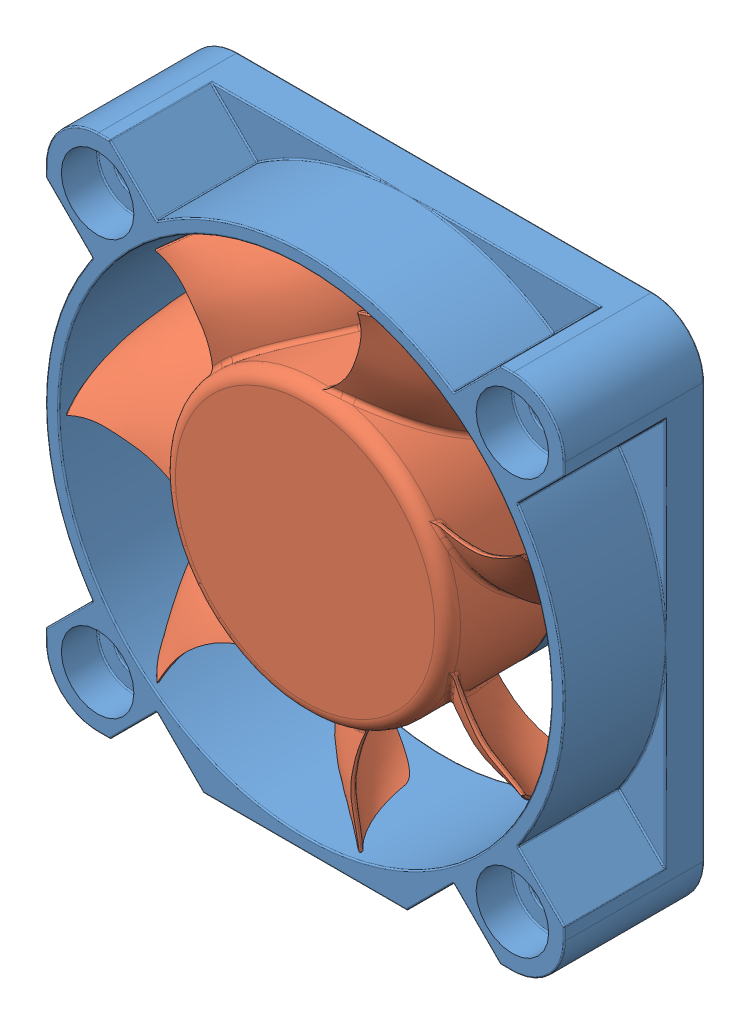
SolidWorks assembly 40mm-fan, configuration По умолчанию. Lengths in mm.
Overall size (40.01 40.11 10.82).
2 component instances, 2 part files, 2 mates.
Components (placement in the parent):
- body^40mm-fan-1: body^40mm-fan [По умолчанию] at (0.9289 7.0036 0) size (40.01 40.11 10.81) (virtual)
- blades^40mm-fan-1: blades^40mm-fan [По умолчанию] at (0.9289 7.0036 -1) size (37.4 37 9.12) (virtual)
Mates (geometry in assembly coordinates):
- Concentric1: concentric anti-aligned: cylinder of body^40mm-fan-1 through (0.9289 7.0036 7.7) axis (0 0 -1) radius 19; cylinder of blades^40mm-fan-1 through (0.9289 7.0036 -1) axis (0 0 1) radius 11
- Coincident1: coincident anti-aligned: plane of body^40mm-fan-1 through (-0.2527 6.56 -1) normal (0 0 1); plane of blades^40mm-fan-1 through (0.9289 7.0036 -1) normal (0 0 -1)
